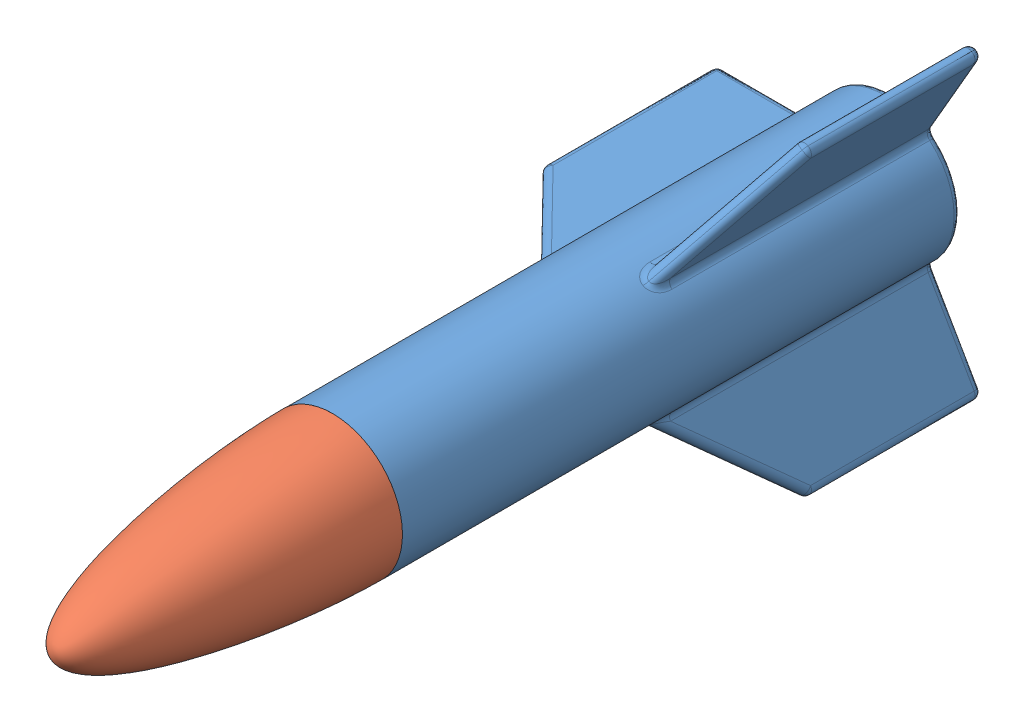
SolidWorks assembly MS-A-0013-Torpedo - 3fins, configuration Default. Lengths in mm.
Overall size (48.87 55.33 152.4).
2 component instances, 2 part files, 1 mates.
Components (placement in the parent):
- MS-P-0042-Torpedo Body-3: MS-P-0042-Torpedo Body [Default] at (40.6803 77.5366 59.8766) size (48.26 55.33 101.6)
- MS-P-0041-Nose Cone-1: MS-P-0041-Nose Cone [Default] at (40.6803 77.5366 161.4766) x (-0.888161 0.459533 0) z (0.459533 0.888161 0) size (25.4 50.8 25.4)
Mates (geometry in assembly coordinates):
- Coincident3: coincident anti-aligned: circle of MS-P-0042-Torpedo Body-3; circle of MS-P-0041-Nose Cone-1
